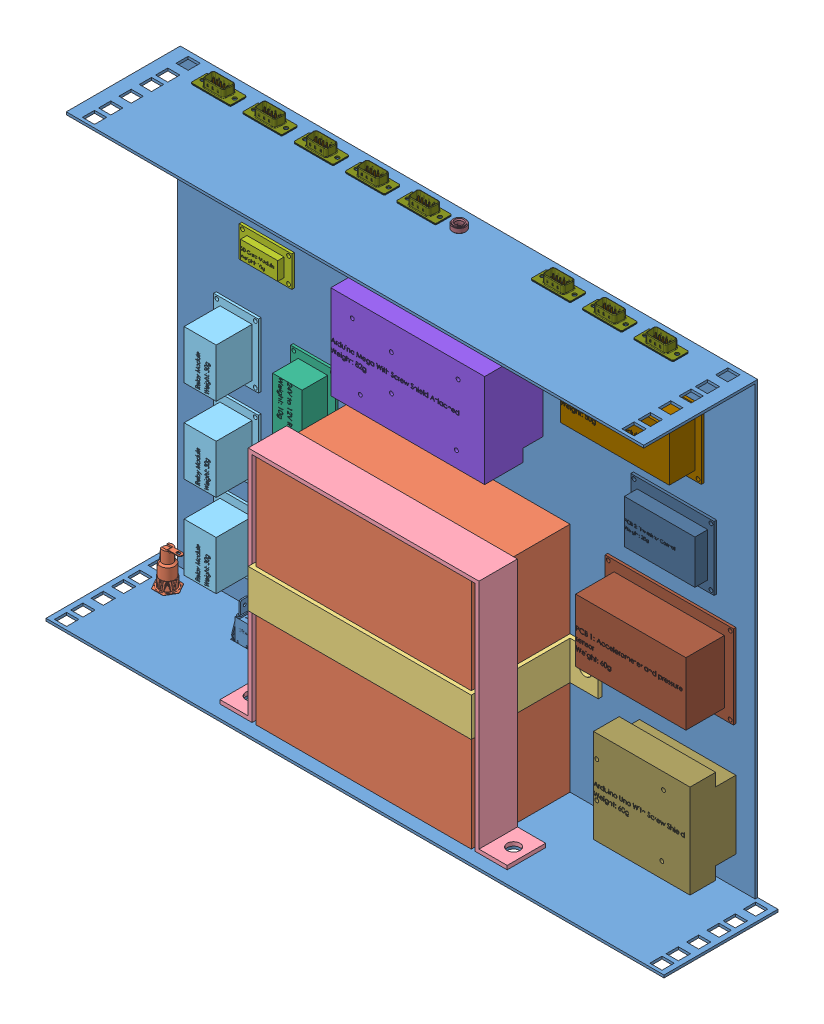
SolidWorks assembly Tray Final, configuration Default. Lengths in mm.
Overall size (482 368.25 88.9).
123 component instances, 20 part files, 70 mates.
Components (placement in the parent):
- Tray fix-1: Tray fix [Default] at (-140.6124 -26.842 47.9853) size (482 352 88.9)
- Battery-1: Battery [Default] at (-227.8124 -19.842 49.9853) size (168 181 77)
- Battery strap 77mm high-1: Battery strap 77mm high [Default] at (-143.8124 -123.842 49.9853) x (-1 0 0) z (0 1 0) size (218 80 30)
- Battery strap 181mm long-1: Battery strap 181mm long [Default] at (-143.8124 -200.842 96.9853) size (224 184 30)
- Relay Module V3-1: Relay Module V3 [Default] at (-318.3124 -155.842 49.9853) x (-1 0 0) z (0 1 0) size (35 30 50)
- Relay Module V3-2: Relay Module V3 [Default] at (-318.3124 -90.842 49.9853) x (-1 0 0) z (0 1 0) size (35 30 50)
- Relay Module V3-3: Relay Module V3 [Default] at (-318.3124 -25.842 49.9853) x (-1 0 0) z (0 1 0) size (35 30 50)
- 24 to 12V regulator-1: 24 to 12V regulator [Default] at (-258.3124 -38.342 49.9853) size (35 65 22)
- SD Card module-1: SD Card module [Default] at (-295.3124 44.158 49.9853) size (41 24 7)
- Arduino Mega with Screw Shield Attached-1: Arduino Mega with Screw Shield Attached [Default] at (-140.8124 55.658 49.9853) size (120 73 45.59)
- PCB 3 TTL TO RS485-1: PCB 3 TTL TO RS485 [Default] at (-2.9124 86.158 49.9853) size (95 52 22)
- PSB 2 Thermistor control-1: PSB 2 Thermistor control [Default] at (22.0876 15.158 49.9853) size (65 50 12)
- PCB 1 accelerometer and pressure sensor-1: PCB 1 accelerometer and pressure sensor [Default] at (19.5876 -57.342 49.9853) size (100 65 32)
- Arduino Uno with Screw shield-1: Arduino Uno with Screw shield [Default] at (31.9501 -151.342 49.9853) size (75.27 73 35.8)
- DC Jack Panel Mount ASSY-1: DC Jack Panel Mount ASSY [Default] at (-133.0964 153.458 63.1731) x (1 0 0) z (0 1 0) size (17.52 16.47 17.63)
  - DC Jack Panel Mount Base-1: DC Jack Panel Mount Base [Default] at origin size (10.2 10.2 17.63)
  - DC Jack Panel Mount Nut-1: DC Jack Panel Mount Nut [Default] at (0 0 -7.35) x (0.866025 -0.5 0) z (0 0 1) size (13.88 11 3.18)
- Assem dt-1: Assem dt [Default] at (-145.1984 170.4412 80.4938) x (-1 0 0) z (0 -1 0) size (30.84 17.69 14.7)
  - D-T -1-1: D-T -1 [Default] at (15.4076 17.3206 20.7832) size (30.84 12.55 4.4)
  - D-T-1: D-T [Default] at (15.4076 17.3206 20.7832) x (-1 0 0) z (0 0 -1) size (30.84 12.55 7.3)
  - D-T -2-1: D-T -2 [Default] at (15.4076 17.3206 24.5832) x (-1 0 0) z (0 0 -1) size (16.3 8.2 5.75)
  - D-t pin-1: D-t pin [Default] at (9.8676 18.7406 15.6832) size (1.5 1.51 13.2)
  - D-t pin-2: D-t pin [Default] at (12.6376 18.7406 15.6832) size (1.5 1.51 13.2)
  - D-t pin-3: D-t pin [Default] at (14.0182 15.9006 15.6832) x (-1 0 0) z (0 0 1) size (1.5 1.51 13.2)
  - D-t pin-4: D-t pin [Default] at (11.2482 15.9006 15.6832) x (-1 0 0) z (0 0 1) size (1.5 1.51 13.2)
  - D-t pin-5: D-t pin [Default] at (18.1776 18.7406 15.6832) size (1.5 1.51 13.2)
  - D-t pin-6: D-t pin [Default] at (15.4076 18.7406 15.6832) size (1.5 1.51 13.2)
  - D-t pin-7: D-t pin [Default] at (16.7882 15.9006 15.6832) x (-1 0 0) z (0 0 1) size (1.5 1.51 13.2)
  - D-t pin-8: D-t pin [Default] at (19.5582 15.9006 15.6832) x (-1 0 0) z (0 0 1) size (1.5 1.51 13.2)
  - D-t pin-9: D-t pin [Default] at (20.9476 18.7406 15.6832) size (1.5 1.51 13.2)
- Assem dt-5: Assem dt [Default] at (-185.203 170.4412 80.4938) x (-1 0 0) z (0 -1 0) size (30.84 17.69 14.7)
  - D-T -1-1: D-T -1 [Default] at (15.4076 17.3206 20.7832) size (30.84 12.55 4.4)
  - D-T-1: D-T [Default] at (15.4076 17.3206 20.7832) x (-1 0 0) z (0 0 -1) size (30.84 12.55 7.3)
  - D-T -2-1: D-T -2 [Default] at (15.4076 17.3206 24.5832) x (-1 0 0) z (0 0 -1) size (16.3 8.2 5.75)
  - D-t pin-1: D-t pin [Default] at (9.8676 18.7406 15.6832) size (1.5 1.51 13.2)
  - D-t pin-2: D-t pin [Default] at (12.6376 18.7406 15.6832) size (1.5 1.51 13.2)
  - D-t pin-3: D-t pin [Default] at (14.0182 15.9006 15.6832) x (-1 0 0) z (0 0 1) size (1.5 1.51 13.2)
  - D-t pin-4: D-t pin [Default] at (11.2482 15.9006 15.6832) x (-1 0 0) z (0 0 1) size (1.5 1.51 13.2)
  - D-t pin-5: D-t pin [Default] at (18.1776 18.7406 15.6832) size (1.5 1.51 13.2)
  - D-t pin-6: D-t pin [Default] at (15.4076 18.7406 15.6832) size (1.5 1.51 13.2)
  - D-t pin-7: D-t pin [Default] at (16.7882 15.9006 15.6832) x (-1 0 0) z (0 0 1) size (1.5 1.51 13.2)
  - D-t pin-8: D-t pin [Default] at (19.5582 15.9006 15.6832) x (-1 0 0) z (0 0 1) size (1.5 1.51 13.2)
  - D-t pin-9: D-t pin [Default] at (20.9476 18.7406 15.6832) size (1.5 1.51 13.2)
- Assem dt-6: Assem dt [Default] at (-265.2121 170.4412 80.4938) x (-1 0 0) z (0 -1 0) size (30.84 17.69 14.7)
  - D-T -1-1: D-T -1 [Default] at (15.4076 17.3206 20.7832) size (30.84 12.55 4.4)
  - D-T-1: D-T [Default] at (15.4076 17.3206 20.7832) x (-1 0 0) z (0 0 -1) size (30.84 12.55 7.3)
  - D-T -2-1: D-T -2 [Default] at (15.4076 17.3206 24.5832) x (-1 0 0) z (0 0 -1) size (16.3 8.2 5.75)
  - D-t pin-1: D-t pin [Default] at (9.8676 18.7406 15.6832) size (1.5 1.51 13.2)
  - D-t pin-2: D-t pin [Default] at (12.6376 18.7406 15.6832) size (1.5 1.51 13.2)
  - D-t pin-3: D-t pin [Default] at (14.0182 15.9006 15.6832) x (-1 0 0) z (0 0 1) size (1.5 1.51 13.2)
  - D-t pin-4: D-t pin [Default] at (11.2482 15.9006 15.6832) x (-1 0 0) z (0 0 1) size (1.5 1.51 13.2)
  - D-t pin-5: D-t pin [Default] at (18.1776 18.7406 15.6832) size (1.5 1.51 13.2)
  - D-t pin-6: D-t pin [Default] at (15.4076 18.7406 15.6832) size (1.5 1.51 13.2)
  - D-t pin-7: D-t pin [Default] at (16.7882 15.9006 15.6832) x (-1 0 0) z (0 0 1) size (1.5 1.51 13.2)
  - D-t pin-8: D-t pin [Default] at (19.5582 15.9006 15.6832) x (-1 0 0) z (0 0 1) size (1.5 1.51 13.2)
  - D-t pin-9: D-t pin [Default] at (20.9476 18.7406 15.6832) size (1.5 1.51 13.2)
- Assem dt-7: Assem dt [Default] at (-225.193 170.4412 80.4938) x (-1 0 0) z (0 -1 0) size (30.84 17.69 14.7)
  - D-T -1-1: D-T -1 [Default] at (15.4076 17.3206 20.7832) size (30.84 12.55 4.4)
  - D-T-1: D-T [Default] at (15.4076 17.3206 20.7832) x (-1 0 0) z (0 0 -1) size (30.84 12.55 7.3)
  - D-T -2-1: D-T -2 [Default] at (15.4076 17.3206 24.5832) x (-1 0 0) z (0 0 -1) size (16.3 8.2 5.75)
  - D-t pin-1: D-t pin [Default] at (9.8676 18.7406 15.6832) size (1.5 1.51 13.2)
  - D-t pin-2: D-t pin [Default] at (12.6376 18.7406 15.6832) size (1.5 1.51 13.2)
  - D-t pin-3: D-t pin [Default] at (14.0182 15.9006 15.6832) x (-1 0 0) z (0 0 1) size (1.5 1.51 13.2)
  - D-t pin-4: D-t pin [Default] at (11.2482 15.9006 15.6832) x (-1 0 0) z (0 0 1) size (1.5 1.51 13.2)
  - D-t pin-5: D-t pin [Default] at (18.1776 18.7406 15.6832) size (1.5 1.51 13.2)
  - D-t pin-6: D-t pin [Default] at (15.4076 18.7406 15.6832) size (1.5 1.51 13.2)
  - D-t pin-7: D-t pin [Default] at (16.7882 15.9006 15.6832) x (-1 0 0) z (0 0 1) size (1.5 1.51 13.2)
  - D-t pin-8: D-t pin [Default] at (19.5582 15.9006 15.6832) x (-1 0 0) z (0 0 1) size (1.5 1.51 13.2)
  - D-t pin-9: D-t pin [Default] at (20.9476 18.7406 15.6832) size (1.5 1.51 13.2)
- Rocker Switch Red LED-2: Rocker Switch Red LED [Default] at (-280.2124 -202.842 67.3853) x (0 0 -1) z (-1 0 0) size (25 38.05 31)
- Fuse-3: Fuse [Predeterminado] at (-355.7124 -174.295 67.9853) x (-1 0 0) z (0 0 1) size (20.79 34.8 18.38)
- Assem dt-9: Assem dt [Default] at (-305.2167 170.4412 80.4938) x (-1 0 0) z (0 -1 0) size (30.84 17.69 14.7)
  - D-T -1-1: D-T -1 [Default] at (15.4076 17.3206 20.7832) size (30.84 12.55 4.4)
  - D-T-1: D-T [Default] at (15.4076 17.3206 20.7832) x (-1 0 0) z (0 0 -1) size (30.84 12.55 7.3)
  - D-T -2-1: D-T -2 [Default] at (15.4076 17.3206 24.5832) x (-1 0 0) z (0 0 -1) size (16.3 8.2 5.75)
  - D-t pin-1: D-t pin [Default] at (9.8676 18.7406 15.6832) size (1.5 1.51 13.2)
  - D-t pin-2: D-t pin [Default] at (12.6376 18.7406 15.6832) size (1.5 1.51 13.2)
  - D-t pin-3: D-t pin [Default] at (14.0182 15.9006 15.6832) x (-1 0 0) z (0 0 1) size (1.5 1.51 13.2)
  - D-t pin-4: D-t pin [Default] at (11.2482 15.9006 15.6832) x (-1 0 0) z (0 0 1) size (1.5 1.51 13.2)
  - D-t pin-5: D-t pin [Default] at (18.1776 18.7406 15.6832) size (1.5 1.51 13.2)
  - D-t pin-6: D-t pin [Default] at (15.4076 18.7406 15.6832) size (1.5 1.51 13.2)
  - D-t pin-7: D-t pin [Default] at (16.7882 15.9006 15.6832) x (-1 0 0) z (0 0 1) size (1.5 1.51 13.2)
  - D-t pin-8: D-t pin [Default] at (19.5582 15.9006 15.6832) x (-1 0 0) z (0 0 1) size (1.5 1.51 13.2)
  - D-t pin-9: D-t pin [Default] at (20.9476 18.7406 15.6832) size (1.5 1.51 13.2)
- Assem dt-10: Assem dt [Default] at (-40.203 170.4412 80.4938) x (-1 0 0) z (0 -1 0) size (30.84 17.69 14.7)
  - D-T -1-1: D-T -1 [Default] at (15.4076 17.3206 20.7832) size (30.84 12.55 4.4)
  - D-T-1: D-T [Default] at (15.4076 17.3206 20.7832) x (-1 0 0) z (0 0 -1) size (30.84 12.55 7.3)
  - D-T -2-1: D-T -2 [Default] at (15.4076 17.3206 24.5832) x (-1 0 0) z (0 0 -1) size (16.3 8.2 5.75)
  - D-t pin-1: D-t pin [Default] at (9.8676 18.7406 15.6832) size (1.5 1.51 13.2)
  - D-t pin-2: D-t pin [Default] at (12.6376 18.7406 15.6832) size (1.5 1.51 13.2)
  - D-t pin-3: D-t pin [Default] at (14.0182 15.9006 15.6832) x (-1 0 0) z (0 0 1) size (1.5 1.51 13.2)
  - D-t pin-4: D-t pin [Default] at (11.2482 15.9006 15.6832) x (-1 0 0) z (0 0 1) size (1.5 1.51 13.2)
  - D-t pin-5: D-t pin [Default] at (18.1776 18.7406 15.6832) size (1.5 1.51 13.2)
  - D-t pin-6: D-t pin [Default] at (15.4076 18.7406 15.6832) size (1.5 1.51 13.2)
  - D-t pin-7: D-t pin [Default] at (16.7882 15.9006 15.6832) x (-1 0 0) z (0 0 1) size (1.5 1.51 13.2)
  - D-t pin-8: D-t pin [Default] at (19.5582 15.9006 15.6832) x (-1 0 0) z (0 0 1) size (1.5 1.51 13.2)
  - D-t pin-9: D-t pin [Default] at (20.9476 18.7406 15.6832) size (1.5 1.51 13.2)
- Assem dt-11: Assem dt [Default] at (-0.1839 170.4412 80.4938) x (-1 0 0) z (0 -1 0) size (30.84 17.69 14.7)
  - D-T -1-1: D-T -1 [Default] at (15.4076 17.3206 20.7832) size (30.84 12.55 4.4)
  - D-T-1: D-T [Default] at (15.4076 17.3206 20.7832) x (-1 0 0) z (0 0 -1) size (30.84 12.55 7.3)
  - D-T -2-1: D-T -2 [Default] at (15.4076 17.3206 24.5832) x (-1 0 0) z (0 0 -1) size (16.3 8.2 5.75)
  - D-t pin-1: D-t pin [Default] at (9.8676 18.7406 15.6832) size (1.5 1.51 13.2)
  - D-t pin-2: D-t pin [Default] at (12.6376 18.7406 15.6832) size (1.5 1.51 13.2)
  - D-t pin-3: D-t pin [Default] at (14.0182 15.9006 15.6832) x (-1 0 0) z (0 0 1) size (1.5 1.51 13.2)
  - D-t pin-4: D-t pin [Default] at (11.2482 15.9006 15.6832) x (-1 0 0) z (0 0 1) size (1.5 1.51 13.2)
  - D-t pin-5: D-t pin [Default] at (18.1776 18.7406 15.6832) size (1.5 1.51 13.2)
  - D-t pin-6: D-t pin [Default] at (15.4076 18.7406 15.6832) size (1.5 1.51 13.2)
  - D-t pin-7: D-t pin [Default] at (16.7882 15.9006 15.6832) x (-1 0 0) z (0 0 1) size (1.5 1.51 13.2)
  - D-t pin-8: D-t pin [Default] at (19.5582 15.9006 15.6832) x (-1 0 0) z (0 0 1) size (1.5 1.51 13.2)
  - D-t pin-9: D-t pin [Default] at (20.9476 18.7406 15.6832) size (1.5 1.51 13.2)
- Assem dt-12: Assem dt [Default] at (39.8207 170.4412 80.4938) x (-1 0 0) z (0 -1 0) size (30.84 17.69 14.7)
  - D-T -1-1: D-T -1 [Default] at (15.4076 17.3206 20.7832) size (30.84 12.55 4.4)
  - D-T-1: D-T [Default] at (15.4076 17.3206 20.7832) x (-1 0 0) z (0 0 -1) size (30.84 12.55 7.3)
  - D-T -2-1: D-T -2 [Default] at (15.4076 17.3206 24.5832) x (-1 0 0) z (0 0 -1) size (16.3 8.2 5.75)
  - D-t pin-1: D-t pin [Default] at (9.8676 18.7406 15.6832) size (1.5 1.51 13.2)
  - D-t pin-2: D-t pin [Default] at (12.6376 18.7406 15.6832) size (1.5 1.51 13.2)
  - D-t pin-3: D-t pin [Default] at (14.0182 15.9006 15.6832) x (-1 0 0) z (0 0 1) size (1.5 1.51 13.2)
  - D-t pin-4: D-t pin [Default] at (11.2482 15.9006 15.6832) x (-1 0 0) z (0 0 1) size (1.5 1.51 13.2)
  - D-t pin-5: D-t pin [Default] at (18.1776 18.7406 15.6832) size (1.5 1.51 13.2)
  - D-t pin-6: D-t pin [Default] at (15.4076 18.7406 15.6832) size (1.5 1.51 13.2)
  - D-t pin-7: D-t pin [Default] at (16.7882 15.9006 15.6832) x (-1 0 0) z (0 0 1) size (1.5 1.51 13.2)
  - D-t pin-8: D-t pin [Default] at (19.5582 15.9006 15.6832) x (-1 0 0) z (0 0 1) size (1.5 1.51 13.2)
  - D-t pin-9: D-t pin [Default] at (20.9476 18.7406 15.6832) size (1.5 1.51 13.2)
Mates (geometry in assembly coordinates):
- Coincident1: coincident anti-aligned: plane of Tray fix-1 through (-140.6124 -26.842 49.9853) normal (0 0 1); plane of Battery-1 through (-227.8124 -19.842 49.9853) normal (0 0 -1)
- Coincident2: coincident anti-aligned: plane of Tray fix-1 through (-140.6124 -200.842 47.9853) normal (0 1 0); plane of Battery-1 through (-227.8124 -200.842 126.9853) normal (0 -1 0)
- Distance1: distance = 138 mm: line of Tray fix-1 through (-365.8124 147.158 49.9853) axis (0 -1 0); plane of Battery-1 through (-227.8124 -19.842 126.9853) normal (-1 0 0)
- Coincident6: coincident anti-aligned: plane of Battery-1 through (-227.8124 -19.842 126.9853) normal (0 0 1); plane of Battery strap 77mm high-1 through (-59.8124 -93.842 126.9853) normal (0 0 -1)
- Coincident7: coincident anti-aligned: plane of Battery-1 through (-227.8124 -19.842 126.9853) normal (-1 0 0); plane of Battery strap 77mm high-1 through (-227.8124 -93.842 126.9853) normal (1 0 0)
- Distance3: distance = 77 mm anti-aligned: plane of Battery strap 77mm high-1 through (-143.8124 -123.842 49.9853) normal (0 -1 0); plane of Tray fix-1 through (-140.6124 -200.842 47.9853) normal (0 1 0)
- Coincident15: coincident anti-aligned: plane of Tray fix-1 through (-140.6124 -200.842 47.9853) normal (0 1 0); plane of Battery strap 181mm long-1 through (-255.8124 -200.842 126.9853) normal (0 -1 0)
- Concentric4: concentric anti-aligned: cylinder of Tray fix-1 through (-245.8124 149.159 111.9853) axis (0 -1 0) radius 5; cylinder of Battery strap 181mm long-1 through (-245.8124 -227.842 111.9853) axis (0 1 0) radius 5
- Concentric5: concentric anti-aligned: cylinder of Tray fix-1 through (-41.8124 149.159 111.9853) axis (0 -1 0) radius 5; circle of Battery strap 181mm long-1
- Coincident20: coincident anti-aligned: plane of Tray fix-1 through (-140.6124 -26.842 49.9853) normal (0 0 1); plane of Relay Module V3-1 through (-318.3124 -155.842 49.9853) normal (0 0 -1)
- Concentric10: concentric anti-aligned: cylinder of Tray fix-1 through (-333.3124 -133.342 19.9853) axis (0 0 1) radius 1.5; cylinder of Relay Module V3-1 through (-333.3124 -133.342 51.9853) axis (0 0 -1) radius 1.5
- Concentric11: concentric anti-aligned: cylinder of Tray fix-1 through (-303.3124 -178.342 19.9853) axis (0 0 1) radius 1.5; cylinder of Relay Module V3-1 through (-303.3124 -178.342 51.9853) axis (0 0 -1) radius 1.5
- Coincident21: coincident anti-aligned: plane of Tray fix-1 through (-140.6124 -26.842 49.9853) normal (0 0 1); plane of Relay Module V3-2 through (-318.3124 -90.842 49.9853) normal (0 0 -1)
- Coincident22: coincident anti-aligned: plane of Tray fix-1 through (-140.6124 -26.842 49.9853) normal (0 0 1); plane of Relay Module V3-3 through (-318.3124 -25.842 49.9853) normal (0 0 -1)
- Concentric12: concentric anti-aligned: cylinder of Tray fix-1 through (-333.3124 -113.342 19.9853) axis (0 0 1) radius 1.5; cylinder of Relay Module V3-2 through (-333.3124 -113.342 51.9853) axis (0 0 -1) radius 1.5
- Concentric13: concentric anti-aligned: cylinder of Tray fix-1 through (-333.3124 -48.342 19.9853) axis (0 0 1) radius 1.5; cylinder of Relay Module V3-3 through (-333.3124 -48.342 51.9853) axis (0 0 -1) radius 1.5
- Concentric14: concentric anti-aligned: cylinder of Tray fix-1 through (-303.3124 -68.342 19.9853) axis (0 0 1) radius 1.5; cylinder of Relay Module V3-2 through (-303.3124 -68.342 51.9853) axis (0 0 -1) radius 1.5
- Concentric15: concentric anti-aligned: cylinder of Tray fix-1 through (-303.3124 -3.342 19.9853) axis (0 0 1) radius 1.5; cylinder of Relay Module V3-3 through (-303.3124 -3.342 51.9853) axis (0 0 -1) radius 1.5
- Coincident23: coincident anti-aligned: plane of Tray fix-1 through (-140.6124 -26.842 49.9853) normal (0 0 1); plane of 24 to 12V regulator-1 through (-258.3124 -38.342 49.9853) normal (0 0 -1)
- Concentric16: concentric anti-aligned: cylinder of Tray fix-1 through (-243.3124 -68.342 19.9853) axis (0 0 1) radius 1.5; cylinder of 24 to 12V regulator-1 through (-243.3124 -68.342 51.9853) axis (0 0 -1) radius 1.5
- Concentric17: concentric anti-aligned: cylinder of Tray fix-1 through (-273.3124 -8.342 19.9853) axis (0 0 1) radius 1.5; cylinder of 24 to 12V regulator-1 through (-273.3124 -8.342 51.9853) axis (0 0 -1) radius 1.5
- Coincident24: coincident anti-aligned: plane of Tray fix-1 through (-140.6124 -26.842 49.9853) normal (0 0 1); plane of SD Card module-1 through (-295.3124 44.158 49.9853) normal (0 0 -1)
- Coincident25: coincident anti-aligned: circle of Tray fix-1; cylinder of SD Card module-1 through (-313.3124 34.658 51.9853) axis (0 0 -1) radius 1.5
- Concentric18: concentric anti-aligned: cylinder of Tray fix-1 through (-277.3124 53.658 47.9843) axis (0 0 1) radius 1.5; cylinder of SD Card module-1 through (-277.3124 53.658 51.9853) axis (0 0 -1) radius 1.5
- Concentric19: concentric anti-aligned: cylinder of Tray fix-1 through (-184.0104 79.919 47.9843) axis (0 0 1) radius 1.5; cylinder of Arduino Mega with Screw Shield Attached-1 through (-184.0104 79.919 65.5753) axis (0 0 -1) radius 1.5
- Concentric20: concentric anti-aligned: cylinder of Tray fix-1 through (-153.5624 72.302 47.9843) axis (0 0 1) radius 1.5; cylinder of Arduino Mega with Screw Shield Attached-1 through (-153.5624 72.302 65.5753) axis (0 0 -1) radius 1.5
- Coincident26: coincident anti-aligned: plane of Tray fix-1 through (-140.6124 -26.842 49.9853) normal (0 0 1); plane of Arduino Mega with Screw Shield Attached-1 through (-140.8124 55.658 49.9853) normal (0 0 -1)
- Coincident27: coincident anti-aligned: plane of Tray fix-1 through (-140.6124 -26.842 49.9853) normal (0 0 1); plane of PCB 3 TTL TO RS485-1 through (-2.9124 86.158 49.9853) normal (0 0 -1)
- Concentric21: concentric anti-aligned: cylinder of Tray fix-1 through (42.0876 109.658 47.9843) axis (0 0 1) radius 1.5; cylinder of PCB 3 TTL TO RS485-1 through (42.0876 109.658 51.9853) axis (0 0 -1) radius 1.5
- Concentric22: concentric anti-aligned: cylinder of Tray fix-1 through (-47.9124 62.658 47.9843) axis (0 0 1) radius 1.5; cylinder of PCB 3 TTL TO RS485-1 through (-47.9124 62.658 51.9853) axis (0 0 -1) radius 1.5
- Concentric23: concentric anti-aligned: cylinder of Tray fix-1 through (-7.9124 37.658 47.9843) axis (0 0 1) radius 1.5; cylinder of PSB 2 Thermistor control-1 through (-7.9124 37.658 51.9853) axis (0 0 -1) radius 1.5
- Concentric24: concentric anti-aligned: cylinder of Tray fix-1 through (52.0876 -7.342 47.9843) axis (0 0 1) radius 1.5; cylinder of PSB 2 Thermistor control-1 through (52.0876 -7.342 51.9853) axis (0 0 -1) radius 1.5
- Concentric25: concentric anti-aligned: cylinder of Tray fix-1 through (67.0876 -27.342 47.9843) axis (0 0 1) radius 1.5; cylinder of PCB 1 accelerometer and pressure sensor-1 through (67.0876 -27.342 51.9853) axis (0 0 -1) radius 1.5
- Coincident28: coincident aligned: cylinder of Tray fix-1 through (-27.9124 -87.342 47.9843) axis (0 0 1) radius 1.5; circle of PCB 1 accelerometer and pressure sensor-1
- Coincident29: coincident anti-aligned: plane of Tray fix-1 through (-140.6124 -26.842 49.9853) normal (0 0 1); plane of PSB 2 Thermistor control-1 through (22.0876 15.158 49.9853) normal (0 0 -1)
- Coincident30: coincident anti-aligned: plane of Tray fix-1 through (-140.6124 -26.842 49.9853) normal (0 0 1); plane of PCB 1 accelerometer and pressure sensor-1 through (19.5876 -57.342 49.9853) normal (0 0 -1)
- Concentric26: concentric anti-aligned: cylinder of Tray fix-1 through (47.6026 -175.753 47.9843) axis (0 0 1) radius 1.5; cylinder of Arduino Uno with Screw shield-1 through (47.6026 -175.753 65.7853) axis (0 0 -1) radius 1.5
- Concentric27: concentric anti-aligned: cylinder of Tray fix-1 through (-3.1624 -132.309 47.9843) axis (0 0 1) radius 1.5; cylinder of Arduino Uno with Screw shield-1 through (-3.1624 -132.309 65.7853) axis (0 0 -1) radius 1.5
- Coincident31: coincident anti-aligned: plane of Tray fix-1 through (-140.6124 -26.842 49.9853) normal (0 0 1); plane of Arduino Uno with Screw shield-1 through (31.9501 -151.342 49.9853) normal (0 0 -1)
- Coincident32: coincident anti-aligned: plane of Tray fix-1 through (-140.6124 147.158 47.9853) normal (0 -1 0); plane of DC Jack Panel Mount ASSY-1/DC Jack Panel Mount Nut-1 through (-133.0964 147.158 63.1731) normal (0 1 0)
- Concentric28: concentric anti-aligned: circle of Tray fix-1; circle of DC Jack Panel Mount ASSY-1/DC Jack Panel Mount Base-1
- Coincident33: coincident anti-aligned: plane of Tray fix-1 through (-365.8124 149.158 49.9853) normal (0 1 0); plane of Assem dt-1/D-T -1-1 through (-175.026 149.158 57.8981) normal (0 -1 0)
- Concentric29: concentric aligned: cylinder of Tray fix-1 through (-173.101 -202.843 63.1731) axis (0 1 0) radius 1.5; cylinder of Assem dt-1/D-T-1 through (-173.101 145.3447 63.1731) axis (0 1 0) radius 1.525
- Parallel2: parallel aligned: cylinder of Tray fix-1 through (-148.0964 -202.843 63.1731) axis (0 1 0) radius 1.5; cylinder of Assem dt-1/D-T-1 through (-148.111 145.3447 63.1731) axis (0 1 0) radius 1.525
- Coincident36: coincident anti-aligned: plane of Tray fix-1 through (-365.8124 149.158 49.9853) normal (0 1 0); plane of Assem dt-5/D-T -1-1 through (-215.0305 149.158 57.8981) normal (0 -1 0)
- Concentric34: concentric aligned: cylinder of Tray fix-1 through (-213.1055 -202.843 63.1731) axis (0 1 0) radius 1.5; cylinder of Assem dt-5/D-T-1 through (-213.1055 145.3447 63.1731) axis (0 1 0) radius 1.525
- Parallel4: parallel aligned: cylinder of Tray fix-1 through (-188.101 -202.843 63.1731) axis (0 1 0) radius 1.5; cylinder of Assem dt-5/D-T-1 through (-188.1155 145.3447 63.1731) axis (0 1 0) radius 1.525
- Coincident39: coincident anti-aligned: plane of Tray fix-1 through (-365.8124 149.158 49.9853) normal (0 1 0); plane of Assem dt-6/D-T -1-1 through (-295.0397 149.158 57.8981) normal (0 -1 0)
- Concentric43: concentric aligned: cylinder of Tray fix-1 through (-293.1147 -202.843 63.1731) axis (0 1 0) radius 1.5; cylinder of Assem dt-6/D-T-1 through (-293.1147 145.3447 63.1731) axis (0 1 0) radius 1.525
- Parallel8: parallel aligned: cylinder of Tray fix-1 through (-268.1101 -202.843 63.1731) axis (0 1 0) radius 1.5; cylinder of Assem dt-6/D-T-1 through (-268.1247 145.3447 63.1731) axis (0 1 0) radius 1.525
- Coincident40: coincident anti-aligned: plane of Tray fix-1 through (-365.8124 149.158 49.9853) normal (0 1 0); plane of Assem dt-7/D-T -1-1 through (-255.0205 149.158 57.8981) normal (0 -1 0)
- Concentric44: concentric aligned: cylinder of Tray fix-1 through (-228.1055 -202.843 63.1731) axis (0 1 0) radius 1.5; cylinder of Assem dt-7/D-T-1 through (-228.1055 145.3447 63.1731) axis (0 1 0) radius 1.525
- Parallel9: parallel aligned: cylinder of Tray fix-1 through (-253.1101 -202.843 63.1731) axis (0 1 0) radius 1.5; cylinder of Assem dt-7/D-T-1 through (-253.0955 145.3447 63.1731) axis (0 1 0) radius 1.525
- Coincident66: coincident anti-aligned: plane of Tray fix-1 through (-365.8124 -202.842 49.9853) normal (0 -1 0); plane of Rocker Switch Red LED-2 through (-280.2124 -202.842 67.3853) normal (0 1 0)
- Coincident69: coincident anti-aligned: plane of Tray fix-1 through (-295.7124 149.159 79.0853) normal (1 0 0); plane of Rocker Switch Red LED-2 through (-295.7124 -198.342 78.0853) normal (-1 0 0)
- Distance5: distance = 2 mm anti-aligned: plane of Rocker Switch Red LED-2 through (-264.9624 -204.942 54.8853) normal (0 0 -1); plane of Tray fix-1 through (-295.7124 149.159 56.8853) normal (0 0 1)
- Coincident73: coincident: plane of Tray fix-1 through (-365.8124 -202.842 49.9853) normal (0 -1 0); plane of Fuse-3 through (-355.7124 -202.842 67.9853) normal (0 1 0)
- Concentric49: concentric aligned: cylinder of Tray fix-1 through (-355.7124 149.159 67.9853) axis (0 -1 0) radius 4; cylinder of Fuse-3 through (-355.7124 -202.842 67.9853) axis (0 -1 0) radius 7.5
- Coincident74: coincident anti-aligned: plane of Tray fix-1 through (-365.8124 149.158 49.9853) normal (0 1 0); plane of Assem dt-9/D-T -1-1 through (-335.0442 149.158 57.8981) normal (0 -1 0)
- Concentric50: concentric aligned: cylinder of Tray fix-1 through (-333.1192 -202.843 63.1731) axis (0 1 0) radius 1.5; cylinder of Assem dt-9/D-T-1 through (-333.1192 145.3447 63.1731) axis (0 1 0) radius 1.525
- Parallel10: parallel aligned: cylinder of Tray fix-1 through (-308.1147 -202.843 63.1731) axis (0 1 0) radius 1.5; cylinder of Assem dt-9/D-T-1 through (-308.1292 145.3447 63.1731) axis (0 1 0) radius 1.525
- Coincident75: coincident anti-aligned: plane of Tray fix-1 through (-365.8124 149.158 49.9853) normal (0 1 0); plane of Assem dt-10/D-T -1-1 through (-70.0305 149.158 57.8981) normal (0 -1 0)
- Concentric52: concentric aligned: cylinder of Tray fix-1 through (-68.1055 -202.843 63.1731) axis (0 1 0) radius 1.5; cylinder of Assem dt-10/D-T-1 through (-68.1055 145.3447 63.1731) axis (0 1 0) radius 1.525
- Parallel11: parallel aligned: cylinder of Tray fix-1 through (-43.101 -202.843 63.1731) axis (0 1 0) radius 1.5; cylinder of Assem dt-10/D-T-1 through (-43.1155 145.3447 63.1731) axis (0 1 0) radius 1.525
- Coincident76: coincident anti-aligned: plane of Tray fix-1 through (-365.8124 149.158 49.9853) normal (0 1 0); plane of Assem dt-11/D-T -1-1 through (-30.0114 149.158 57.8981) normal (0 -1 0)
- Concentric54: concentric aligned: cylinder of Tray fix-1 through (-3.0964 -202.843 63.1731) axis (0 1 0) radius 1.5; cylinder of Assem dt-11/D-T-1 through (-3.0964 145.3447 63.1731) axis (0 1 0) radius 1.525
- Parallel12: parallel aligned: cylinder of Tray fix-1 through (-28.101 -202.843 63.1731) axis (0 1 0) radius 1.5; cylinder of Assem dt-11/D-T-1 through (-28.0864 145.3447 63.1731) axis (0 1 0) radius 1.525
- Coincident77: coincident anti-aligned: plane of Tray fix-1 through (-365.8124 149.158 49.9853) normal (0 1 0); plane of Assem dt-12/D-T -1-1 through (9.9931 149.158 57.8981) normal (0 -1 0)
- Concentric56: concentric aligned: cylinder of Tray fix-1 through (36.9081 -202.843 63.1731) axis (0 1 0) radius 1.5; cylinder of Assem dt-12/D-T-1 through (36.9081 145.3447 63.1731) axis (0 1 0) radius 1.525
- Parallel13: parallel aligned: cylinder of Tray fix-1 through (11.9036 -202.843 63.1731) axis (0 1 0) radius 1.5; cylinder of Assem dt-12/D-T-1 through (11.9181 145.3447 63.1731) axis (0 1 0) radius 1.525
